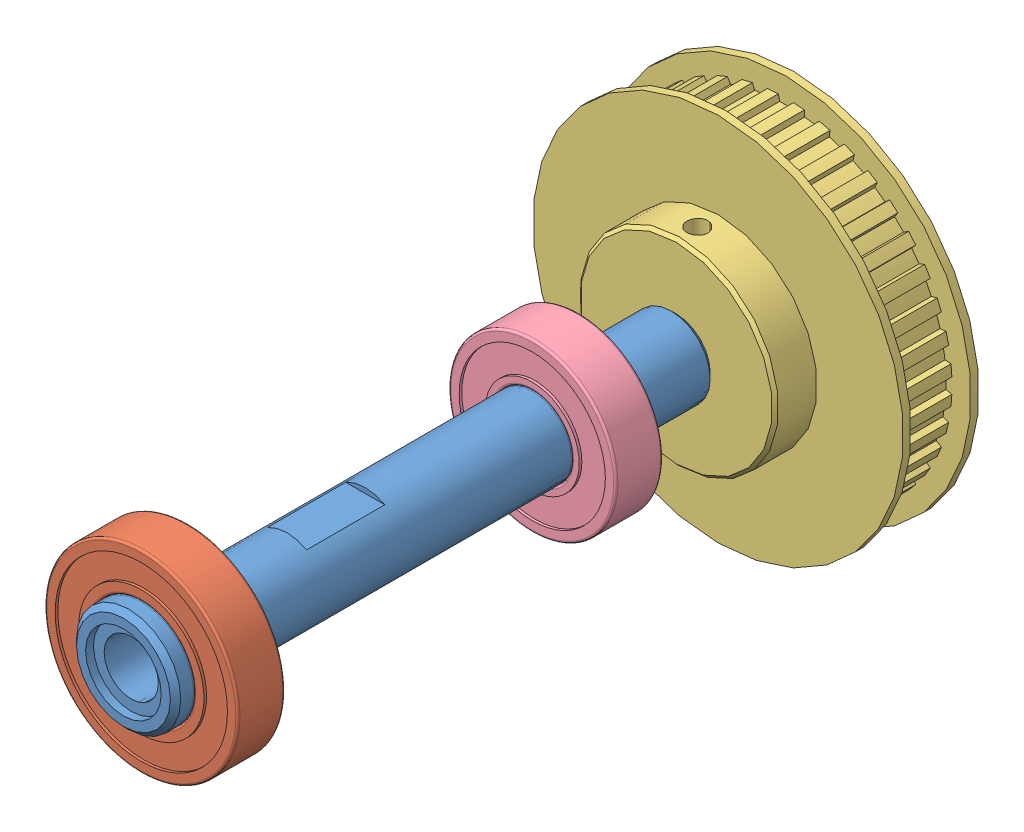
SolidWorks assembly Modélisation axe moteur, configuration Default. Lengths in mm.
Overall size (71 71 139.34).
4 component instances, 4 part files, 9 mates.
Components (placement in the parent):
- 72 502 0C Axe arrière-1: 72 502 0C Axe arrière [Défaut] x (0 1 0) z (-1 0 0) size (20 139.34 20)
- 99 00 011 Roulement 6904 LLU 20x37x9-1: 99 00 011 Roulement 6904 LLU 20x37x9 [Défaut] at (0 0 137.9109) x (0 0 -1) z (0.427228 -0.904144 0) size (9 37 37)
- a9-40-5m09-1: a9-40-5m09 [Default] at (0 0 10.9) x (0 0 1) z (0 -1 0) size (22.5 71 71)
- 99 00 005 Roulement 6002 ZZ 15x32x9-1: 99 00 005 Roulement 6002 ZZ 15x32x9 [Défaut] at (0 0 63) x (0 0 -1) z (0.434519 0.900662 0) size (9 32 32)
Mates (geometry in assembly coordinates):
- Coïncidente6: coincident: point of 72 502 0C Axe arrière-1; point of assembly
- Coaxiale1: concentric: cylinder of 72 502 0C Axe arrière-1 through (0 0 0) axis (0 0 -1) radius 5; cylinder of a9-40-5m09-1 through (0 0 33.4) axis (0 0 -1) radius 5
- Coïncidente2: coincident: plane of 72 502 0C Axe arrière-1 through (0 5 33.4) normal (0 0 -1); plane of a9-40-5m09-1 through (-6.5054 6.5054 33.4) normal (0 0 1)
- Coaxiale2: concentric anti-aligned: cylinder of 72 502 0C Axe arrière-1 through (0 0 0) axis (0 0 -1) radius 10; cylinder of 99 00 011 Roulement 6904 LLU 20x37x9-1 through (0 0 137.9109) axis (0 0 1) radius 10
- Coïncidente7: coincident anti-aligned: plane of 72 502 0C Axe arrière-1 through (0 0 0) normal (-1 0 0); plane of assembly through (0 0 0) normal (1 0 0)
- Coïncidente8: coincident anti-aligned: plane of 72 502 0C Axe arrière-1; plane of assembly through (0 0 0) normal (0 0 1)
- Parallèle1: parallel anti-aligned: plane of a9-40-5m09-1 through (0 0 10.9) normal (0 -1 0); plane of 72 502 0C Axe arrière-1 through (3 4 22.4) normal (0 1 0)
- Coaxiale3: concentric: cylinder of 72 502 0C Axe arrière-1 through (0 0 0) axis (0 0 -1) radius 7.5; cylinder of 99 00 005 Roulement 6002 ZZ 15x32x9-1 through (0 0 63) axis (0 0 1) radius 7.5
- Coïncidente9: coincident aligned: circle of 72 502 0C Axe arrière-1; plane of 99 00 005 Roulement 6002 ZZ 15x32x9-1 through (-8.106 3.9107 52) normal (0 0 -1)
